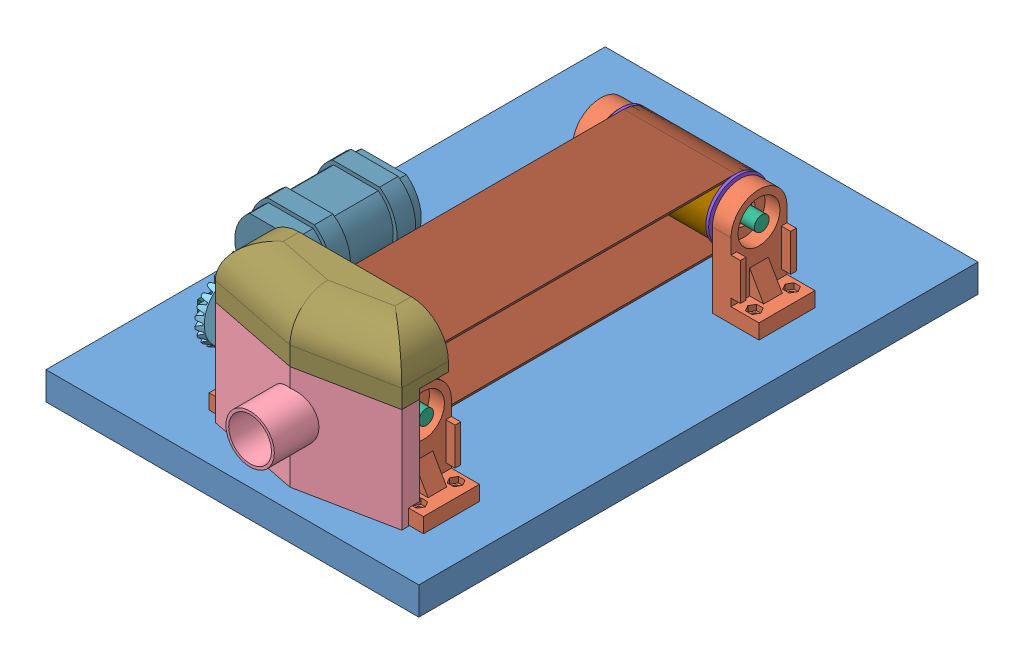
SolidWorks assembly Lijadora, configuration Default. Lengths in mm.
Overall size (200 101 310.5).
31 component instances, 15 part files, 38 mates.
Components (placement in the parent):
- Base-1: Base [Default] at origin size (200 15 300)
- Pata-1: Pata [Default] at (152.5 55 -40) size (25 55 30)
- Pata-2: Pata [Default] at (152.5 55 -220) size (25 55 30)
- Pata-3: Pata [Default] at (87.5 55 -40) x (-1 0 0) z (0 0 -1) size (25 55 30)
- Pata-4: Pata [Default] at (87.5 55 -220) x (-1 0 0) z (0 0 -1) size (25 55 30)
- Traba aire-1: Traba aire [Default] at (88 15 -55) size (64 37.22 35)
- Aspiradora1-1: Aspiradora1 [Default] at (120 15 -10.8604) x (-1 0 0) z (0 0 -1) size (100 56 41)
- straight bevel gear_iso-1: straight bevel gear_iso [ISO - Straight bevel gear 1.5M 24GT 12PT 20PA 8FW ---24O12H20MD8.0N] at (61.6002 55 -40) x (-1 0 0) z (0 0 -1) size (15.41 36.86 36.86)
- Cilindro2a-1: Cilindro2a [Default] at (120 55 -220) size (88 43.71 43.71)
  - EjeCilindro-1: EjeCilindro [Default] at origin size (44 20 20)
  - TacoCilindro-2: TacoCilindro [Default] at (-7 5 0) size (15 5 5)
  - TacoCilindro-4: TacoCilindro [Default] at (-7 -2.5 4.3301) size (15 5 5)
  - TacoCilindro-5: TacoCilindro [Default] at (-7 -2.5 -4.3301) size (15 5 5)
  - Tope Lija-1: Tope Lija [Default] at (-31.5 0 0) x (1 0 0) z (0 -0.866025 0.5) size (6.5 32 32)
  - Tope Lija-2: Tope Lija [Default] at (31.5 0 0) x (-1 0 0) z (0 0 1) size (6.5 32 32)
  - Caucho-1: Caucho [Default] at (-30 0 0) x (1 0 0) z (0 -0.73568 0.677329) size (60 30 30)
  - EjeCilindro-2: EjeCilindro [Default] x (-1 0 0) z (0 -0.866025 0.5) size (44 20 20)
- Cilindro2b-1: Cilindro2b [Default] at (120 55 -40) size (109 43.71 43.71)
  - EjeCilindro-1: EjeCilindro [Default] at origin size (44 20 20)
  - TacoCilindro-2: TacoCilindro [Default] at (-7 5 0) size (15 5 5)
  - TacoCilindro-4: TacoCilindro [Default] at (-7 -2.5 4.3301) size (15 5 5)
  - TacoCilindro-5: TacoCilindro [Default] at (-7 -2.5 -4.3301) size (15 5 5)
  - Tope Lija-1: Tope Lija [Default] at (-31.5 0 0) x (1 0 0) z (0 -0.866025 0.5) size (6.5 32 32)
  - Tope Lija-2: Tope Lija [Default] at (31.5 0 0) x (-1 0 0) z (0 0 1) size (6.5 32 32)
  - Caucho-1: Caucho [Default] at (-30 0 0) size (60 30 30)
  - EjeCilindro2-1: EjeCilindro2 [Default] x (-1 0 0) z (0 -0.866025 0.5) size (65 20 20)
- Lija-2: Lija [Default] at (90 55 -40) size (60 32 212)
- Aspiradora2-1: Aspiradora2 [Default] at (120 71 -10.8604) x (-1 0 0) z (0 0 -1) size (100 35 35)
- straight bevel pinion_iso-1: straight bevel pinion_iso [ISO - Straight bevel pinion 1.5M12PT 24GT 20PA 8FW ---12O8H25MD5.0N] at (50.0281 55 -58.7074) x (0 0 1) z (-0.431865 0.901938 0) size (14.77 20.57 20.57)
- Motor-1: Motor [Default] at (50.0281 55 -131.2708) size (50 51 80)
- Base Motor-1: Base Motor [Default] at (15.0281 15 -146.2708) size (70 7 80)
Mates (geometry in assembly coordinates):
- Concentric1: concentric aligned: cylinder of Base-1 through (170 0 -50) axis (0 1 0) radius 2; cylinder of Pata-1 through (170 15 -50) axis (0 1 0) radius 2
- Concentric2: concentric aligned: cylinder of Base-1 through (170 0 -30) axis (0 1 0) radius 2; cylinder of Pata-1 through (170 15 -30) axis (0 1 0) radius 2
- Coincident1: coincident anti-aligned: plane of Base-1 through (0 15 0) normal (0 1 0); plane of Pata-1 through (162.5 15 -25) normal (0 -1 0)
- Concentric3: concentric aligned: cylinder of Base-1 through (170 0 -230) axis (0 1 0) radius 2; cylinder of Pata-2 through (170 15 -230) axis (0 1 0) radius 2
- Concentric4: concentric aligned: cylinder of Base-1 through (170 0 -210) axis (0 1 0) radius 2; cylinder of Pata-2 through (170 15 -210) axis (0 1 0) radius 2
- Coincident2: coincident anti-aligned: plane of Base-1 through (0 15 0) normal (0 1 0); plane of Pata-2 through (162.5 15 -205) normal (0 -1 0)
- Concentric5: concentric aligned: cylinder of Base-1 through (70 0 -50) axis (0 1 0) radius 2; cylinder of Pata-3 through (70 15 -50) axis (0 1 0) radius 2
- Concentric6: concentric aligned: cylinder of Base-1 through (70 0 -30) axis (0 1 0) radius 2; cylinder of Pata-3 through (70 15 -30) axis (0 1 0) radius 2
- Coincident3: coincident anti-aligned: plane of Base-1 through (0 15 0) normal (0 1 0); plane of Pata-3 through (77.5 15 -55) normal (0 -1 0)
- Concentric7: concentric aligned: cylinder of Base-1 through (70 0 -230) axis (0 1 0) radius 2; cylinder of Pata-4 through (70 15 -230) axis (0 1 0) radius 2
- Concentric8: concentric aligned: cylinder of Base-1 through (70 0 -210) axis (0 1 0) radius 2; cylinder of Pata-4 through (70 15 -210) axis (0 1 0) radius 2
- Coincident4: coincident anti-aligned: plane of Base-1 through (0 15 0) normal (0 1 0); plane of Pata-4 through (77.5 15 -235) normal (0 -1 0)
- Distance3: distance = 0.5 mm anti-aligned: plane of Pata-1 through (152.5 55 -40) normal (-1 0 0); plane of Traba aire-1 through (152 55 -40) normal (1 0 0)
- Coincident7: coincident anti-aligned: plane of Base-1 through (0 15 0) normal (0 1 0); plane of Traba aire-1 through (152 15 -55) normal (0 -1 0)
- Coincident8: coincident aligned: plane of Pata-1 through (162.5 15 -55) normal (0 0 -1); plane of Traba aire-1 through (152 37 -55) normal (0 0 -1)
- Distance5: distance = 0.5 mm anti-aligned: plane of Pata-1 through (167.5 27 -28) normal (0 0 -1); plane of Aspiradora1-1 through (168 71 -28.5) normal (0 0 1)
- Distance6: distance = 0.5 mm anti-aligned: plane of Pata-1 through (162.5 55 -40) normal (1 0 0); plane of Aspiradora1-1 through (163 71 -28.5) normal (-1 0 0)
- Coincident10: coincident anti-aligned: plane of Base-1 through (0 15 0) normal (0 1 0); plane of Aspiradora1-1 through (120 15 -10.8604) normal (0 -1 0)
- Concentric9: concentric aligned: cylinder of Pata-2 through (162.5 55 -220) axis (-1 0 0) radius 11.25; cylinder of Cilindro2a-1/EjeCilindro-1 through (164 55 -220) axis (-1 0 0) radius 3.95
- Distance7: distance = 1 mm anti-aligned: plane of Cilindro2a-1/Tope Lija-1 through (88.5 55 -220) normal (-1 0 0); plane of Pata-4 through (87.5 55 -220) normal (1 0 0)
- Concentric10: concentric aligned: cylinder of Pata-1 through (162.5 55 -40) axis (-1 0 0) radius 11.25; cylinder of Cilindro2b-1/EjeCilindro-1 through (164 55 -40) axis (-1 0 0) radius 3.95
- Distance8: distance = 1 mm anti-aligned: plane of Pata-3 through (87.5 55 -40) normal (1 0 0); plane of Cilindro2b-1/Tope Lija-1 through (88.5 55 -40) normal (-1 0 0)
- Distance9: distance = 2 mm aligned: plane of straight bevel gear_iso-1 through (57 55 -40) normal (-1 0 0); plane of Cilindro2b-1/EjeCilindro2-1 through (55 55 -40) normal (-1 0 0)
- Concentric11: concentric aligned: cylinder of Cilindro2a-1/Caucho-1 through (150 55 -220) axis (-1 0 0) radius 15; cylinder of Lija-2 through (150 55 -220) axis (-1 0 0) radius 15
- Concentric12: concentric aligned: cylinder of Cilindro2b-1/Caucho-1 through (150 55 -40) axis (-1 0 0) radius 15; cylinder of Lija-2 through (150 55 -40) axis (-1 0 0) radius 15
- Coincident14: coincident anti-aligned: plane of Cilindro2a-1/Tope Lija-1 through (90 55 -220) normal (1 0 0); plane of Lija-2 through (90 55 -40) normal (-1 0 0)
- Coincident15: coincident aligned: plane of Aspiradora1-1 through (170 71 -20.8604) normal (0.196116 0 0.980581); plane of Aspiradora2-1 through (170 76 -20.8604) normal (0.196116 0 0.980581)
- Coincident16: coincident aligned: plane of Aspiradora1-1 through (70 71 -20.8604) normal (-0.196116 0 0.980581); plane of Aspiradora2-1 through (70 76 -20.8604) normal (-0.196116 0 0.980581)
- Coincident17: coincident anti-aligned: plane of Aspiradora1-1 through (120 71 -10.8604) normal (0 1 0); plane of Aspiradora2-1 through (120 71 -10.8604) normal (0 -1 0)
- Perpendicular1: perpendicular: cylinder of Cilindro2b-1/EjeCilindro2-1 through (55 55 -40) axis (1 0 0) radius 3.95; cylinder of straight bevel pinion_iso-1 through (50.0281 55 -33.7074) axis (0 0 -1) radius 2.5
- Coincident18: coincident: point of straight bevel gear_iso-1; point of straight bevel pinion_iso-1
- Concentric13: concentric aligned: cylinder of straight bevel gear_iso-1 through (41.6001 55 -40) axis (1 0 0) radius 4; cylinder of Cilindro2b-1/EjeCilindro2-1 through (55 55 -40) axis (1 0 0) radius 3.95
- Concentric14: concentric aligned: cylinder of straight bevel pinion_iso-1 through (50.0281 55 -33.7074) axis (0 0 -1) radius 2.5; cylinder of Motor-1 through (50.0281 55 -131.2708) axis (0 0 -1) radius 2
- Coincident19: coincident aligned: plane of straight bevel pinion_iso-1 through (50.0281 55 -51.2708) normal (0 0 1); plane of Motor-1 through (50.0281 55 -51.2708) normal (0 0 1)
- Parallel1: parallel: axis of straight bevel pinion_iso-1 through (50.0281 55 -65.0001) axis (0 0 1); plane of assembly
- Coincident21: coincident anti-aligned: plane of Base-1 through (0 15 0) normal (0 1 0); plane of Base Motor-1 through (15.0281 15 -146.2708) normal (0 -1 0)
- Distance10: distance = 10 mm aligned: plane of Motor-1 through (25.0281 55 -116.2708) normal (-1 0 0); plane of Base Motor-1 through (15.0281 22 -146.2708) normal (-1 0 0)
- Distance11: distance = 15 mm aligned: plane of Base Motor-1 through (15.0281 22 -66.2708) normal (0 0 1); plane of Motor-1 through (50.0281 55 -81.2708) normal (0 0 1)
